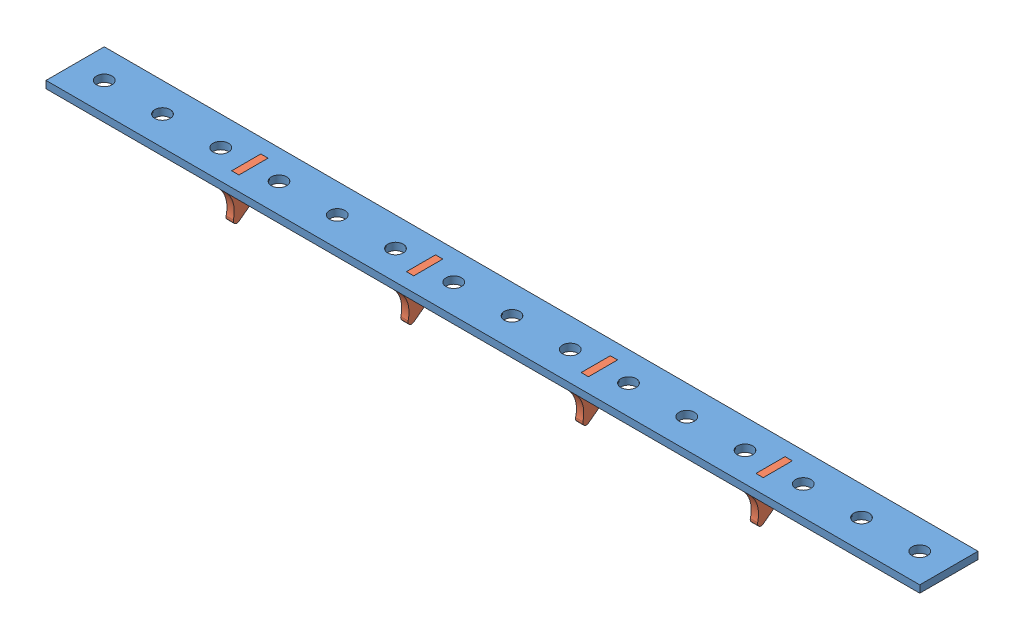
SolidWorks assembly FS2-FR-PB-A-0018-V1, PEDALBOX MOUNTING ASSEMBLY, configuration Default. Lengths in mm.
Overall size (381 17.77 25.4).
5 component instances, 2 part files, 4 mates.
Components (placement in the parent):
- FS2-FR-PB-P-0019-V1, PEDALBOX MOUTING RAIL-1: FS2-FR-PB-P-0019-V1, PEDALBOX MOUTING RAIL [Default] at origin size (381 3.17 25.4)
- FS-2-FR-PB-P-0019-V1, PEDALBOX MOUNTING RAIL SUPPORT-1: FS-2-FR-PB-P-0019-V1, PEDALBOX MOUNTING RAIL SUPPORT [Default] at (77.7875 0 0) x (0 0 1) z (-1 0 0) size (25.4 17.77 3.17)
- FS-2-FR-PB-P-0019-V1, PEDALBOX MOUNTING RAIL SUPPORT-2: FS-2-FR-PB-P-0019-V1, PEDALBOX MOUNTING RAIL SUPPORT [Default] at (153.9875 0 0) x (0 0 1) z (-1 0 0) size (25.4 17.77 3.17)
- FS-2-FR-PB-P-0019-V1, PEDALBOX MOUNTING RAIL SUPPORT-3: FS-2-FR-PB-P-0019-V1, PEDALBOX MOUNTING RAIL SUPPORT [Default] at (230.1875 0 0) x (0 0 1) z (-1 0 0) size (25.4 17.77 3.17)
- FS-2-FR-PB-P-0019-V1, PEDALBOX MOUNTING RAIL SUPPORT-4: FS-2-FR-PB-P-0019-V1, PEDALBOX MOUNTING RAIL SUPPORT [Default] at (306.3875 0 0) x (0 0 1) z (-1 0 0) size (25.4 17.77 3.17)
Mates (geometry in assembly coordinates):
- InPlace1: in place: plane of FS2-FR-PB-P-0019-V1, PEDALBOX MOUTING RAIL-1 through (77.7875 0 -19.05) normal (-1 0 0); plane of FS-2-FR-PB-P-0019-V1, PEDALBOX MOUNTING RAIL SUPPORT-1 through (77.7875 0 0) normal (-1 0 0); moOrthogonalPlaneRef_w of FS2-FR-PB-P-0019-V1, PEDALBOX MOUTING RAIL-1 through (77.7875 0 -19.05) normal (-1 0 0); plane of FS-2-FR-PB-P-0019-V1, PEDALBOX MOUNTING RAIL SUPPORT-1 through (77.7875 0 0) normal (0 1 0); plane of FS2-FR-PB-P-0019-V1, PEDALBOX MOUTING RAIL-1 through (77.7875 0 -19.05) normal (-1 0 0); plane of FS-2-FR-PB-P-0019-V1, PEDALBOX MOUNTING RAIL SUPPORT-1 through (77.7875 0 0) normal (0 0 1); plane of FS2-FR-PB-P-0019-V1, PEDALBOX MOUTING RAIL-1 through (77.7875 0 -19.05) normal (-1 0 0); unknown of FS-2-FR-PB-P-0019-V1, PEDALBOX MOUNTING RAIL SUPPORT-1
- Coincident1: coincident aligned: plane of ?; plane of ?
- Coincident2: coincident aligned: moOrthogonalPlaneRef_w of FS2-FR-PB-A-0019-V1, PEDALBOX MOUTING RAIL-1 through (77.7875 0 0) normal (0 1 0); plane of Part2^FS2-FR-PB-A-0018-V1, PEDALBOX MOUNTING-1 through (77.7875 0 0) normal (0 1 0)
- Coincident3: coincident anti-aligned: moOrthogonalPlaneRef_w of FS2-FR-PB-A-0019-V1, PEDALBOX MOUTING RAIL-1 through (77.7875 0 0) normal (0 0 -1); plane of Part2^FS2-FR-PB-A-0018-V1, PEDALBOX MOUNTING-1 through (77.7875 0 0) normal (0 0 1)
